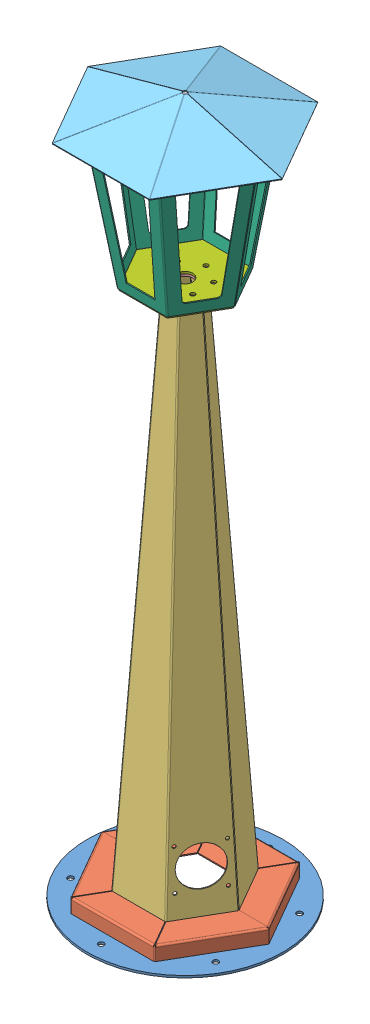
SolidWorks assembly gardenlight, configuration Predeterminado. Lengths in mm.
Overall size (280 999 280).
15 component instances, 8 part files, 6 mates.
Components (placement in the parent):
- standard-complete-1: standard-complete [Predeterminado] at origin size (280 766.09 280)
  - flangebottom-1: flangebottom [Predeterminado] at origin size (280 3 280)
  - base-2: base [Predeterminado] at (0 3 0) size (240.29 20.14 105.17)
  - base-3: base [Predeterminado] at (0 3 0) x (-1 0 0) z (0 0 -1) size (240.29 20.14 105.17)
  - standard-1: standard [Socket] at (0 23 0) size (153.28 740.12 66.5)
  - standard-2: standard [Cable] at (0 23 0) x (-1 0 0) z (0 0 -1) size (153.28 740.12 66.5)
  - flange-top-1: flange-top [Predeterminado] at (0 763.091 0) size (90 3 90)
- hoodcomplete-1: hoodcomplete [Predeterminado] at (0 959.7982 0) size (278.1 39.24 241.34)
  - hood-1: hood [Predeterminado] at origin size (278.1 39.63 120.67)
  - hood-2: hood [Predeterminado] x (-1 0 0) z (0 0 -1) size (278.1 39.63 120.67)
- shade-complete-1: shade-complete [Predeterminado] at (0 766.091 0) size (210.99 203 182.97)
  - shade1-1: shade1 [Predeterminado] at (0 3 0) size (210.99 200.27 91.49)
  - shade1-2: shade1 [Predeterminado] at (0 3 0) x (-1 0 0) z (0 0 -1) size (210.99 200.27 91.49)
  - shade-bottom-2: shade-bottom [Predeterminado] at origin size (138.56 3 120)
  - Pieza2^shade-complete-1: Pieza2^shade-complete [Predeterminado] at origin size (20 3 180) (virtual)
Mates (geometry in assembly coordinates):
- Coincidente1: coincident aligned: plane of ? through (0 1029.0735 0) normal (0 0 1)
- Coincidente2: coincident aligned: plane of ? through (0 1029.0735 0) normal (1 0 0)
- Coincidente3: coincident aligned: plane of ? through (0 766.091 0) normal (0 0 1)
- Coincidente4: coincident aligned: plane of ? through (0 766.091 0) normal (1 0 0)
- Coincidente5: coincident anti-aligned: plane of standard-complete-1/flange-top-1 through (0 766.091 0) normal (0 1 0); plane of shade-complete-1/shade-bottom-2 through (0 766.091 0) normal (0 -1 0)
- Coincidente6: coincident: plane of hoodcomplete-1/hood-1 through (-9.6595 994.654 5.5769) normal (0.263944 -0.952424 -0.152388); line of shade-complete-1/shade1-1 through (-53.8235 968.8685 90.2417) axis (-0.5 0 -0.866025)
